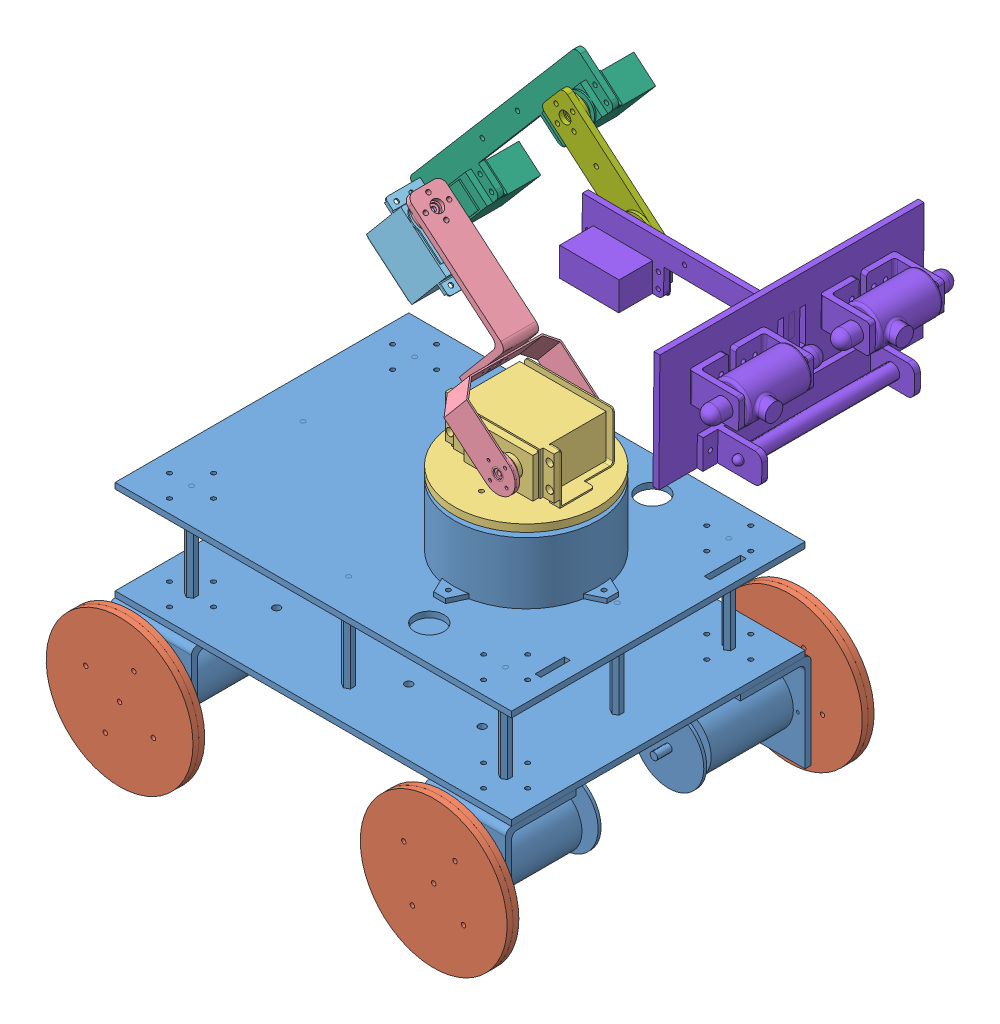
SolidWorks assembly exa_robot16_right, configuration Default. Lengths in mm.
Overall size (452.74 461.66 342.18).
11 component instances, 8 part files, 26 mates.
Components (placement in the parent):
- base_robot-1: base_robot [Default] at (14.2374 -23.114 -6.4589) size (270 179.13 234)
- roda_robot_fix-1: roda_robot_fix [Default] at (268.1239 -5.9891 251.6556) x (0.408711 0.912664 0) z (0 0 1) size (100 100 21)
- roda_robot_fix-2: roda_robot_fix [Default] at (-24.7206 118.9318 251.6556) x (-0.199609 -0.979876 0) z (0 0 1) size (100 100 21)
- roda_robot_fix-3: roda_robot_fix [Default] at (-43.3679 96.894 162.7099) x (0.933321 0.359042 0) z (0 0 -1) size (100 100 21)
- roda_robot_fix-4: roda_robot_fix [Default] at (229.5868 134.8934 162.7099) x (0.816348 -0.57756 0) z (0 0 -1) size (100 100 21)
- link1_robot-1: link1_robot [Default] at (14.2374 -23.114 -6.4589) size (98 43 98)
- link2_robot-1: link2_robot [Default] at (14.2374 -23.114 -6.4589) size (99.47 123.93 66)
- link3_robot-1: link3_robot [Default] at (14.2374 -23.114 -6.4589) size (56.44 54.96 29)
- link4_robot-1: link4_robot [Default] at (11.4345 -22.4006 -6.4589) x (0.999966 -0.008267 0) z (0 0 1) size (137.73 155 42.35)
- link5_robot-1: link5_robot [Default] at (11.4345 -22.4006 -6.4589) x (0.999966 -0.008267 0) z (0 0 1) size (81.1 72.97 14)
- link6_eof_robot-1: link6_eof_robot [Default] at (11.4345 -22.4006 -6.4589) x (0.999966 -0.008267 0) z (0 0 1) size (184.63 80 180)
Mates (geometry in assembly coordinates):
- Coincident1: coincident anti-aligned: plane of base_robot-1 through (258.5015 16.6149 311.1827) normal (0 0 1); plane of roda_robot_fix-1 through (235.6028 60.827 311.1827) normal (0 0 -1)
- Concentric1: concentric aligned: cylinder of base_robot-1 through (235.6028 60.827 324.1827) axis (0 0 -1) radius 2.5; cylinder of roda_robot_fix-1 through (235.6028 60.827 324.1827) axis (0 0 -1) radius 2.5
- Concentric2: concentric aligned: cylinder of base_robot-1 through (235.6028 60.827 90.1827) axis (0 0 1) radius 2.5; cylinder of roda_robot_fix-4 through (235.6028 60.827 90.1827) axis (0 0 1) radius 2.5
- Coincident3: coincident anti-aligned: plane of base_robot-1 through (212.704 16.6149 103.1827) normal (0 0 -1); plane of roda_robot_fix-4 through (235.6028 60.827 103.1827) normal (0 0 1)
- Coincident4: coincident anti-aligned: plane of base_robot-1 through (-1.296 105.0391 311.1827) normal (0 0 1); plane of roda_robot_fix-2 through (21.6028 60.827 311.1827) normal (0 0 -1)
- Concentric3: concentric aligned: cylinder of base_robot-1 through (21.6028 60.827 324.1827) axis (0 0 -1) radius 2.5; cylinder of roda_robot_fix-2 through (21.6028 60.827 324.1827) axis (0 0 -1) radius 2.5
- Coincident5: coincident anti-aligned: plane of base_robot-1 through (-1.296 16.6149 103.1827) normal (0 0 -1); plane of roda_robot_fix-3 through (21.6028 60.827 103.1827) normal (0 0 1)
- Concentric4: concentric aligned: cylinder of base_robot-1 through (21.6028 60.827 90.1827) axis (0 0 1) radius 2.5; cylinder of roda_robot_fix-3 through (21.6028 60.827 90.1827) axis (0 0 1) radius 2.5
- Coincident6: coincident anti-aligned: plane of base_robot-1 through (183.8898 208.9523 217.0887) normal (0 1 0); plane of link1_robot-1 through (173.6028 208.9523 207.1827) normal (0 -1 0)
- Concentric5: concentric aligned: cylinder of base_robot-1 through (173.6028 189.6967 207.1827) axis (0 1 0) radius 2.8131; cylinder of link1_robot-1 through (173.6028 204.9523 207.1827) axis (0 1 0) radius 3
- Coincident7: coincident anti-aligned: plane of link1_robot-1 through (189.1028 233.9523 239.1727) normal (0 0 1); plane of link2_robot-1 through (189.1028 233.9523 239.1727) normal (0 0 -1)
- Concentric6: concentric anti-aligned: cylinder of link1_robot-1 through (189.1028 233.9523 239.1727) axis (0 0 -1) radius 3; cylinder of link2_robot-1 through (189.1028 233.9523 236.1727) axis (0 0 1) radius 3
- Concentric7: concentric anti-aligned: cylinder of link2_robot-1 through (108.8974 331.277 208.7585) axis (0.642788 0.766044 0) radius 3; cylinder of link3_robot-1 through (110.8257 333.5751 208.7585) axis (-0.642788 -0.766044 0) radius 2.9972
- Coincident9: coincident anti-aligned: plane of link2_robot-1 through (110.8257 333.5751 208.7585) normal (-0.642788 -0.766044 0); plane of link3_robot-1 through (110.8257 333.5751 208.7585) normal (0.642788 0.766044 0)
- Coincident10: coincident anti-aligned: plane of link3_robot-1 through (99.1297 316.2635 192.7915) normal (0 0 -1); plane of link4_robot-1 through (99.1297 316.2635 192.7915) normal (0 0 1)
- Concentric8: concentric anti-aligned: cylinder of link3_robot-1 through (99.1297 316.2635 189.7915) axis (0 0 1) radius 3; cylinder of link4_robot-1 through (99.1297 316.2635 192.7915) axis (0 0 -1) radius 2.9972
- Coincident11: coincident anti-aligned: plane of link4_robot-1 through (191.6635 423.9248 192.7915) normal (0 0 1); plane of link5_robot-1 through (191.6635 423.9248 192.7915) normal (0 0 -1)
- Concentric9: concentric anti-aligned: cylinder of link4_robot-1 through (191.6635 423.9248 192.7915) axis (0 0 -1) radius 2.9972; cylinder of link5_robot-1 through (191.6635 423.9248 189.7915) axis (0 0 1) radius 3
- Coincident12: coincident anti-aligned: plane of link5_robot-1 through (241.87 381.0843 200.7915) normal (0 0 1); plane of link6_eof_robot-1 through (241.87 381.0843 200.7915) normal (0 0 -1)
- Concentric10: concentric anti-aligned: cylinder of link5_robot-1 through (241.87 381.0843 203.7915) axis (0 0 -1) radius 3; cylinder of link6_eof_robot-1 through (241.87 381.0843 200.7915) axis (0 0 1) radius 2.9972
- LimitAngle1: limit planar angle = 2.443461 rad anti-aligned: plane of link1_robot-1 through (173.6028 213.9523 207.1827) normal (0 1 0); plane of link2_robot-1 through (166.9546 268.2017 195.8793) normal (0.642788 0.766044 0)
- LimitAngle2: limit planar angle = 1.570796 rad anti-aligned: plane of link3_robot-1 through (93.6106 327.8772 218.7915) normal (-0.766044 0.642788 0); plane of link2_robot-1 through (109.4871 290.3828 220.7585) normal (0 0 1)
- LimitAngle3: limit planar angle = 1.562529 rad aligned: plane of link4_robot-1 through (100.5792 302.5054 177.361) normal (-0.649099 -0.760704 0); plane of link3_robot-1 through (93.6106 327.8772 218.7915) normal (-0.766044 0.642788 0)
- LimitAngle4: limit planar angle = 0 rad aligned: plane of link4_robot-1 through (190.214 437.683 177.361) normal (0.649099 0.760704 0); plane of link5_robot-1 through (190.3243 440.8425 198.7915) normal (0.649099 0.760704 0)
- LimitAngle5: limit planar angle = 2.268928 rad anti-aligned: plane of link5_robot-1 through (174.7459 422.5856 198.7915) normal (-0.649099 -0.760704 0); plane of link6_eof_robot-1 through (224.6686 374.3358 216.222) normal (-0.999966 0.008267 0)
- LimitAngle9: limit planar angle = 1.570796 rad anti-aligned: plane of link1_robot-1 through (203.1028 247.9523 225.1827) normal (1 0 0); plane of base_robot-1 through (200.3661 159.827 307.1827) normal (0 0 1)
